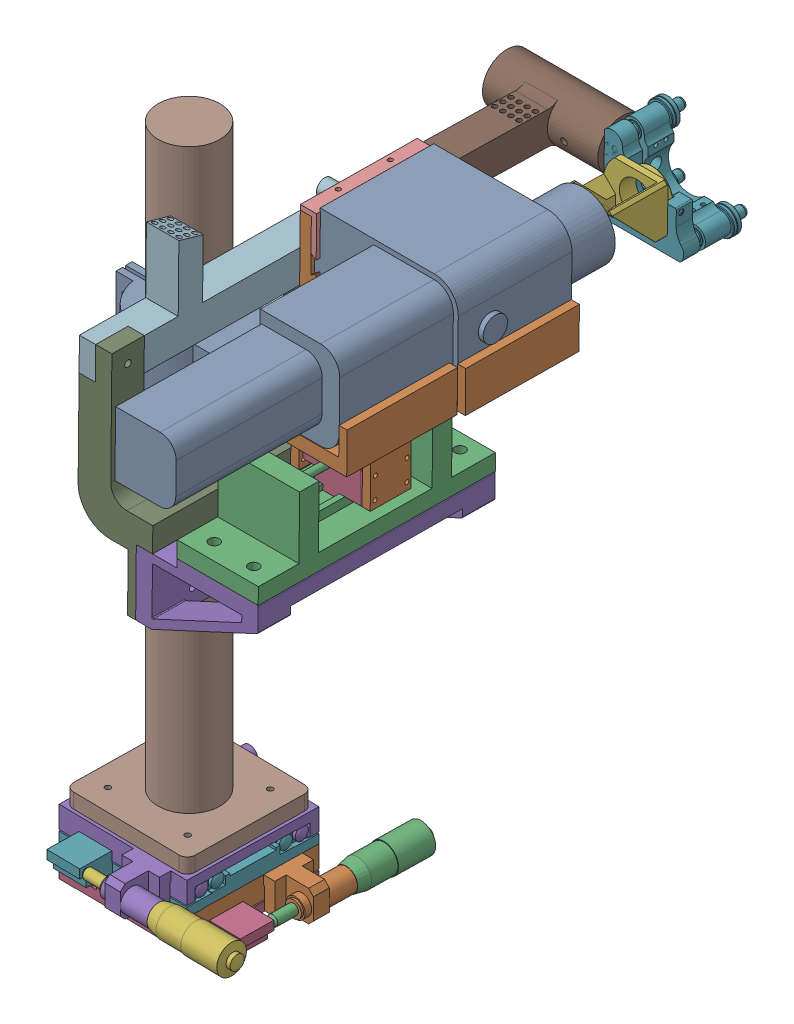
SolidWorks assembly Assem1_1, configuration Default. Lengths in mm.
Overall size (233.25 424.79 347.53).
19 component instances, 16 part files, 0 mates.
Components (placement in the parent):
- OCT3__X2_98108a2d_X0_-1: OCT3__X2_98108a2d_X0_ [Default] at (258.7843 148.9299 51.5651) x (1 0 0) z (0 0.010244 0.999948) size (91.25 60.2 267.12)
- OCT mount v2_1-1: OCT mount v2_1 [Default] at (332.9843 133.27 169.5817) x (0 -0.010244 -0.999948) z (1 0 0) size (140 93.2 100.25)
- Lead screw_1-1: Lead screw_1 [Default] at (339.3843 95.9905 93.6783) x (0 0.010244 0.999948) z (-1 0 0) size (146 48 50)
- Lead screw platform_1-1: Lead screw platform_1 [Default] at (295.2843 112.009 144.2082) x (0 0.010244 0.999948) z (-1 0 0) size (25.59 26.17 38.2)
- Lead screw mount v2_1-1: Lead screw mount v2_1 [Default] at (289.3843 90.9908 93.7295) x (0 0.010244 0.999948) z (-1 0 0) size (146 45 75)
- Mirror holder attachment__X2_98108a2d_X0_-1: Mirror holder attachment__X2_98108a2d_X0_ [Default] at (298.5903 171.7086 -29.3445) x (1 0 0) z (0 0.010244 0.999948) size (36.11 31.26 40.64)
- Mirror holder assembled_1-1: Mirror holder assembled_1 [Default] at (316.3298 250.0283 -2.0805) x (0 0.999948 -0.010244) z (0 -0.010244 -0.999948) size (53.98 128.56 42.58)
  - Newport-U100-A3H.stp_1-1: Newport-U100-A3H.stp_1 [Default] at (-172.1028 -102.6999 -107.2719) size (53.97 53.98 42.58)
  - Mirror shaft_1-1: Mirror shaft_1 [Default] at (-78.0363 -104.445 43.1749) x (-0.381849 0 -0.924225) z (0.924225 0 -0.381849) size (12.68 76.17 12.68)
- Beam splitter holder mount v2_1-1: Beam splitter holder mount v2_1 [Default] at (264.3843 82.3845 229.8248) x (1 0 0) z (0 0.010244 0.999948) size (76 133.24 146)
- Body1_1-1: Body1_1 [Default] at (248.3843 164.2783 93.2174) x (0 0.0198 0.999804) z (-1 0 0) size (152.5 35 71)
- Body2_1-1: Body2_1 [Default] at (248.3843 164.2269 92.9792) x (0 0.010244 0.999948) z (-1 0 0) size (156 60.22 20)
- Z shaft mount_1-1: Z shaft mount_1 [Default] at (168.3843 68.6702 111.2542) x (0 0 1) z (-1 0 0) size (60 40 100)
- z_shaft assembled_1-1: z_shaft assembled_1 [Default] at (206.4995 -196.4964 136.3676) x (0.016785 0 -0.999859) z (0.999859 0 0.016785) size (155.6 404.76 140.9)
  - B11-80CZ.step_1-1: B11-80CZ.step_1 [Default] at (24.4701 -2.1391 -38.5314) x (1 0 0) z (0 1 0) size (130.2 117.3 20.22)
  - B11-80CZ.step_1-2: B11-80CZ.step_1 [Default] at (24.4701 17.6609 -38.5314) x (0 0 1) z (0 1 0) size (130.2 117.3 20.22)
  - z shaft_1-1: z shaft_1 [Default] at (-13.6299 37.6609 -0.4314) size (76.2 364.74 76.2)
- Beam splitter holder mount fixture_1-1: Beam splitter holder mount fixture_1 [Default] at (213.3843 88.6702 111.2542) x (0 0 1) z (-1 0 0) size (60 20 10)
- OCT Rail_1-1: OCT Rail_1 [Default] at (258.9843 182.7025 56.5694) x (0 0.010244 0.999948) z (-1 0 0) size (72 24.61 10)
